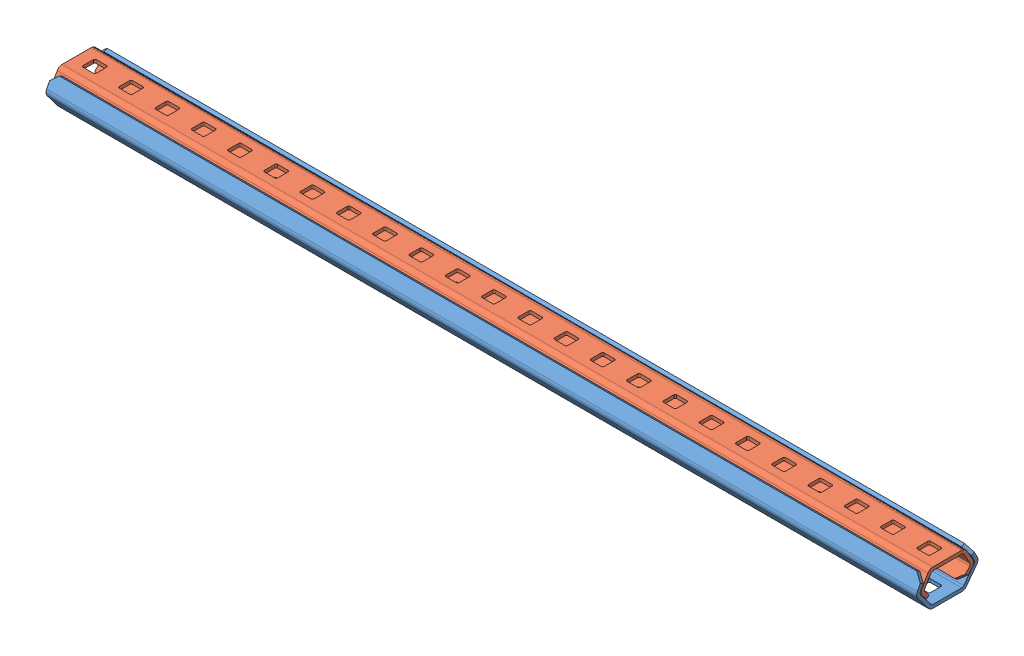
SolidWorks assembly Linear Slides, configuration Default. Lengths in mm.
Overall size (304.8 12.55 21.48).
2 component instances, 2 part files, 0 mates.
Components (placement in the parent):
- VL-SLIDE-O-24 RevA-1: VL-SLIDE-O-24 RevA [Default] at (-82.0341 36.6522 18.3873) size (304.8 11.82 21.48)
- VL-SLIDE-I-24 RevA-1: VL-SLIDE-I-24 RevA [Default] at (-82.0341 49.2009 60.165) x (1 0 0) z (0 0 -1) size (304.8 10.36 18.34)
